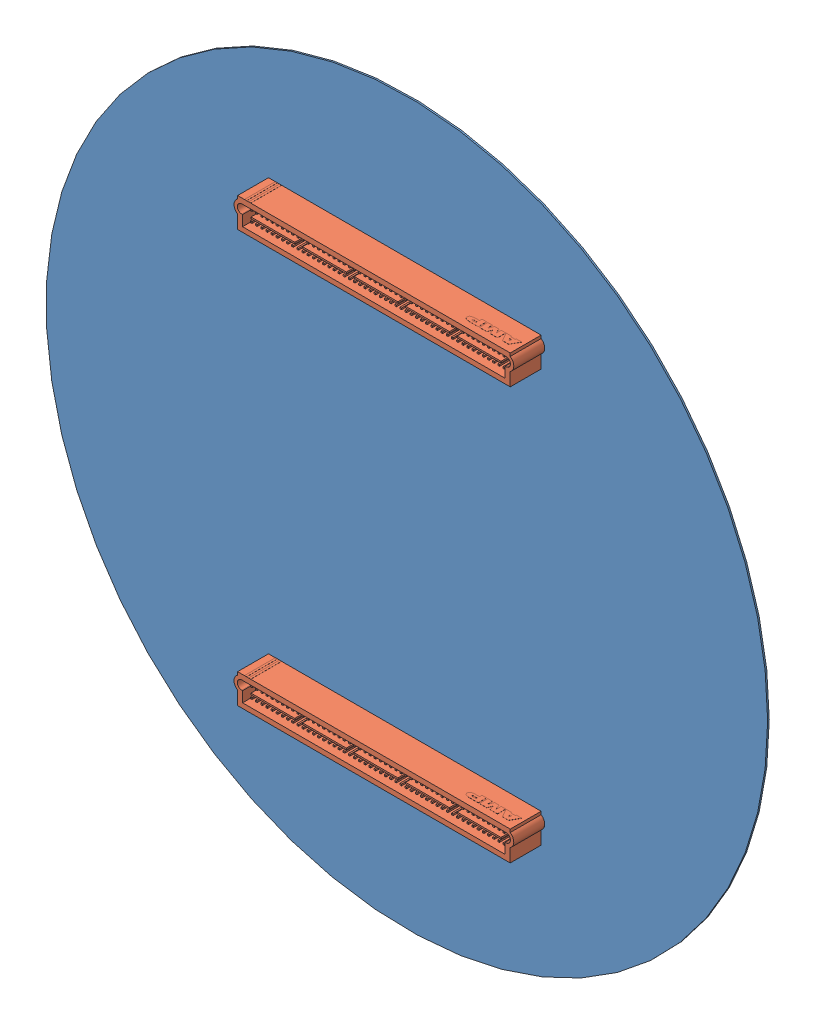
SolidWorks assembly Kanaloa_v2.0.0_Waho, configuration Default. Lengths in mm.
Overall size (177.8 177.8 11.81).
5 component instances, 2 part files, 0 mates.
Components (placement in the parent):
- Board-1: Board [Default] at (0 0 -0.3912) size (177.8 177.8 0.39)
- Kanaloa_v2.0.0_Waho_1-1: Kanaloa_v2.0.0_Waho_1 [Default] at origin size (68.94 7.29 11.81)
  - c-5536272-04-o1-3d-1: c-5536272-04-o1-3d [Default] at (113.792 165.1001 7.62) x (-1 0 0) z (0 0 1) size (68.94 7.29 11.81)
- Kanaloa_v2.0.0_Waho_1_2-1: Kanaloa_v2.0.0_Waho_1_2 [Default] at origin size (68.94 7.29 11.81)
  - c-5536272-04-o1-3d-1: c-5536272-04-o1-3d [Default] at (113.792 63.5001 7.62) x (-1 0 0) z (0 0 1) size (68.94 7.29 11.81)
